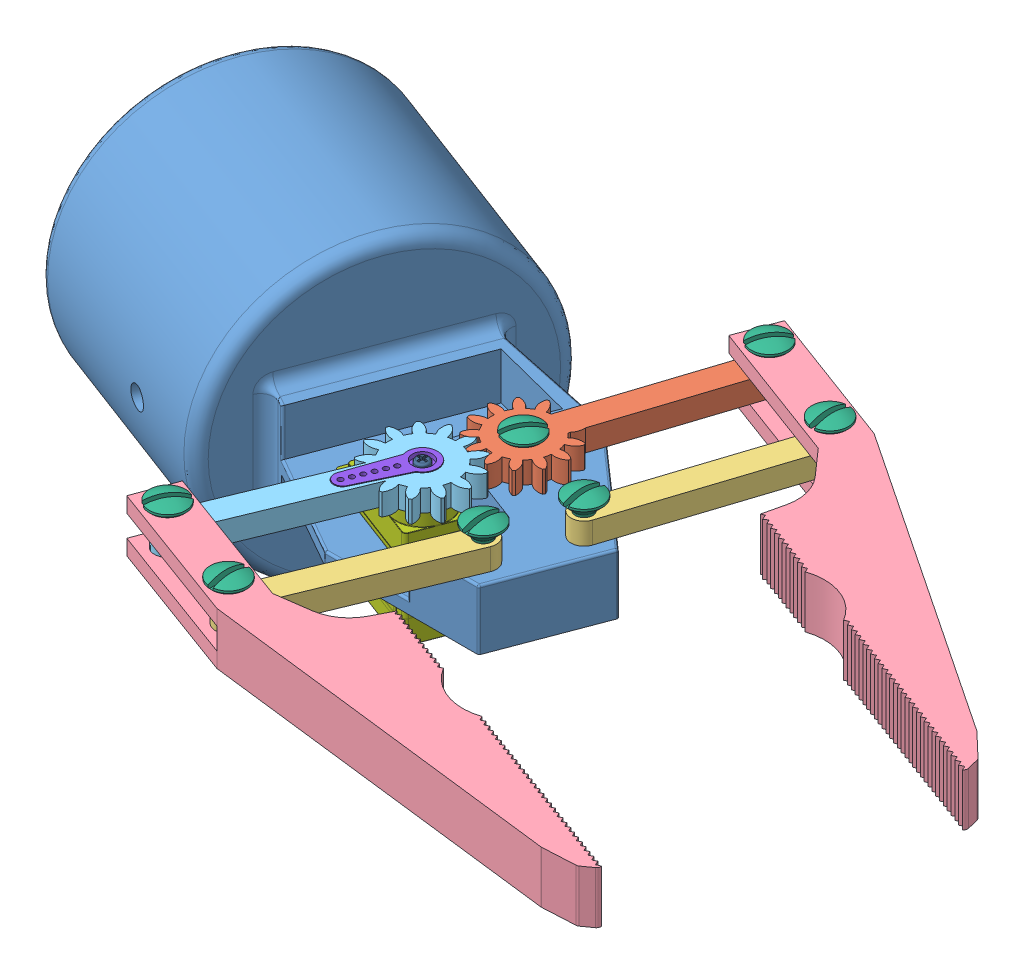
SolidWorks assembly ClawMK2, configuration Default. Lengths in mm.
Overall size (235.04 69 163.29).
19 component instances, 10 part files, 45 mates.
Components (placement in the parent):
- Base-1: Base [Default] at (-1.2919 74.4344 -5.5304) x (-0.353674 0 0.935369) z (-0.935369 0 -0.353674) size (69 69 125)
- Gear2_nocutout-1: Gear2_nocutout [Default] at (67.5688 95.9472 -64.8108) x (0 1 0) z (-0.438891 0 0.89854) size (5 20.52 57.89)
- Connector-1: Connector [Default] at (33.7567 88.2344 -25.927) x (0.308447 0 -0.951241) z (0.951241 0 0.308447) size (51 5 6)
- Claw-3: Claw [Default] at (30.1882 84.7344 -51.2331) x (0.937424 0 0.348189) z (-0.348189 0 0.937424) size (127.47 12 26.59)
- Gear1-2: Gear1 [Default] at (-16.659 95.9472 84.4421) x (0 1 0) z (-0.240649 0 -0.970612) size (5 40.44 50.3)
- Claw-4: Claw [Default] at (-7.186 96.7344 50.0535) x (0.938321 0 0.345766) z (0.345766 0 -0.938321) size (127.47 12 26.59)
- Connector-3: Connector [Default] at (11.8915 88.2344 33.1211) x (-0.3804 0 0.924822) z (-0.924822 0 -0.3804) size (51 5 6)
- countersunk slotted raised head screw_iso-1: countersunk slotted raised head screw_iso [ISO 2010 - M4 x 12 - 12N] at (18.4704 98.6344 -55.5855) x (0 -1 0) z (-0.546944 0 0.837169) size (12.98 8.4 8.31)
- countersunk slotted raised head screw_iso-3: countersunk slotted raised head screw_iso [ISO 2010 - M4 x 12 - 12N] at (40.6968 98.6344 -47.33) x (0 -1 0) z (0 0 1) size (12.98 8.4 8.31)
- countersunk slotted raised head screw_iso-4: countersunk slotted raised head screw_iso [ISO 2010 - M4 x 12 - 12N] at (26.8166 97.4344 -4.5241) x (0 -1 0) z (0 0 1) size (12.98 8.4 8.31)
- countersunk slotted raised head screw_iso-5: countersunk slotted raised head screw_iso [ISO 2010 - M4 x 12 - 12N] at (20.4505 97.4344 12.3126) x (0 -1 0) z (0 0 1) size (12.98 8.4 8.31)
- countersunk slotted raised head screw_iso-6: countersunk slotted raised head screw_iso [ISO 2010 - M4 x 12 - 12N] at (-18.9151 98.6344 45.7314) x (0 -1 0) z (-0.546944 0 0.837169) size (12.98 8.4 8.31)
- countersunk slotted raised head screw_iso-7: countersunk slotted raised head screw_iso [ISO 2010 - M4 x 12 - 12N] at (3.3325 98.6344 53.9296) x (0 -1 0) z (0 0 1) size (12.98 8.4 8.31)
- countersunk slotted raised head screw_iso-8: countersunk slotted raised head screw_iso [ISO 2010 - M4 x 12 - 12N] at (4.5903 95.1344 -12.7796) x (0 -1 0) z (-0.546944 0 0.837169) size (12.98 8.4 8.31)
- SG90 - Micro Servo 9g - Tower Pro.1-1: SG90 - Micro Servo 9g - Tower Pro.1 [Peça] at (-6.618 72.2844 2.2915) x (-0.935369 0 -0.353674) z (0.353674 0 -0.935369) size (32.1 29.95 12.4)
- SG90 - Micro Servo 9g - Tower Pro.2-3: SG90 - Micro Servo 9g - Tower Pro.2 [Peça] at (-1.8008 93.3844 4.1129) x (0.379469 0 -0.925204) z (0.925204 0 0.379469) size (19.5 3.8 6.9)
- SG90 - Micro Servo 9g - Tower Pro.5-1: SG90 - Micro Servo 9g - Tower Pro.5 [BS EN ISO 7045 - M2 x 8 - Z - 8S] at (-19.6196 81.5344 -2.6246) x (0 -1 0) z (0 0 1) size (9.57 4.8 4.8)
- SG90 - Micro Servo 9g - Tower Pro.5-2: SG90 - Micro Servo 9g - Tower Pro.5 [BS EN ISO 7045 - M2 x 8 - Z - 8S] at (6.3836 81.5344 7.2075) x (0 -1 0) z (0 0 1) size (9.57 4.8 4.8)
- SG90 - Micro Servo 9g - Tower Pro.6-5: SG90 - Micro Servo 9g - Tower Pro.6 [BS EN ISO 7045 - M2 x 4 - Z - 4S] at (-1.8008 93.6844 4.1129) x (0 -1 0) z (0 0 1) size (5.28 3.1 3.1)
Mates (geometry in assembly coordinates):
- Coincident3: coincident anti-aligned: plane of Base-1 through (-1.2919 88.2344 -5.5304) normal (0 1 0); plane of Gear2_nocutout-1 through (0.3646 88.2344 -12.9042) normal (0 -1 0)
- Concentric2: concentric anti-aligned: cylinder of Base-1 through (26.8166 84.4344 -4.5241) axis (0 1 0) radius 1.85; cylinder of Connector-1 through (26.8166 93.2344 -4.5241) axis (0 -1 0) radius 2
- Coincident8: coincident anti-aligned: plane of Base-1 through (-1.2919 88.2344 -5.5304) normal (0 1 0); plane of Connector-1 through (26.8166 88.2344 -4.5241) normal (0 -1 0)
- Concentric5: concentric aligned: cylinder of Connector-1 through (40.6968 93.2344 -47.33) axis (0 -1 0) radius 2; cylinder of Claw-3 through (40.6968 96.7344 -47.33) axis (0 -1 0) radius 2
- Coincident11: coincident anti-aligned: plane of Connector-1 through (26.8166 93.2344 -4.5241) normal (0 1 0); plane of Claw-3 through (15.5242 93.2344 -62.0136) normal (0 -1 0)
- Concentric11: concentric aligned: cylinder of Base-1 through (4.5903 84.4344 -12.7796) axis (0 1 0) radius 1.85; cylinder of Gear2_nocutout-1 through (4.5903 88.2344 -12.7796) axis (0 1 0) radius 2
- Coincident17: coincident anti-aligned: plane of Base-1 through (-1.2919 88.2344 -5.5304) normal (0 1 0); plane of Gear2_nocutout-1 through (0.3646 88.2344 -12.9042) normal (0 -1 0)
- Concentric12: concentric anti-aligned: cylinder of Gear2_nocutout-1 through (18.4704 88.2344 -55.5855) axis (0 1 0) radius 2; cylinder of Claw-3 through (18.4704 96.7344 -55.5855) axis (0 -1 0) radius 2
- Coincident18: coincident anti-aligned: plane of Gear2_nocutout-1 through (0.3646 93.2344 -12.9042) normal (0 1 0); plane of Claw-3 through (15.5242 93.2344 -62.0136) normal (0 -1 0)
- Coincident19: coincident anti-aligned: plane of Base-1 through (-1.2919 88.2344 -5.5304) normal (0 1 0); plane of Gear1-2 through (1.7395 88.2344 1.3199) normal (0 -1 0)
- Concentric14: concentric aligned: cylinder of Gear1-2 through (-18.9151 88.2344 45.7314) axis (0 1 0) radius 2; cylinder of Claw-4 through (-18.9151 84.7344 45.7314) axis (0 1 0) radius 2
- Coincident20: coincident anti-aligned: plane of Gear1-2 through (1.7395 93.2344 1.3199) normal (0 1 0); plane of Claw-4 through (-25.3355 93.2344 48.6942) normal (0 -1 0)
- Concentric16: concentric anti-aligned: cylinder of Base-1 through (20.4505 84.4344 12.3126) axis (0 1 0) radius 1.85; cylinder of Connector-3 through (20.4505 93.2344 12.3126) axis (0 -1 0) radius 2
- Coincident21: coincident anti-aligned: plane of Base-1 through (-1.2919 88.2344 -5.5304) normal (0 1 0); plane of Connector-3 through (20.4505 88.2344 12.3126) normal (0 -1 0)
- Concentric17: concentric anti-aligned: cylinder of Claw-4 through (3.3325 84.7344 53.9296) axis (0 1 0) radius 2; cylinder of Connector-3 through (3.3325 93.2344 53.9296) axis (0 -1 0) radius 2
- Coincident22: coincident anti-aligned: plane of Claw-4 through (-25.3355 93.2344 48.6942) normal (0 -1 0); plane of Connector-3 through (20.4505 93.2344 12.3126) normal (0 1 0)
- GearMate1: gear = 1 : 1 mm: cylinder of Gear2_nocutout-1 through (4.5903 88.2344 -12.7796) axis (0 1 0) radius 10.3821; cylinder of Gear1-2 through (-1.8008 88.2344 4.1129) axis (0 1 0) radius 7.7506
- Coincident23: coincident anti-aligned: plane of Claw-4 through (-25.3355 93.2344 48.6942) normal (0 -1 0); plane of Connector-3 through (20.4505 93.2344 12.3126) normal (0 1 0)
- Concentric19: concentric anti-aligned: cylinder of Connector-3 through (20.4505 93.2344 12.3126) axis (0 -1 0) radius 2; cylinder of countersunk slotted raised head screw_iso-5 through (20.4505 113.3094 12.3126) axis (0 1 0) radius 2
- Coincident25: coincident anti-aligned: plane of Base-1 through (20.4505 84.4344 12.3126) normal (0 1 0); plane of countersunk slotted raised head screw_iso-5 through (20.4505 84.4344 12.3126) normal (0 -1 0)
- Coincident26: coincident anti-aligned: plane of Base-1 through (26.8166 84.4344 -4.5241) normal (0 1 0); plane of countersunk slotted raised head screw_iso-4 through (26.8166 84.4344 -4.5241) normal (0 -1 0)
- Concentric20: concentric anti-aligned: cylinder of Connector-1 through (26.8166 93.2344 -4.5241) axis (0 -1 0) radius 2; cylinder of countersunk slotted raised head screw_iso-4 through (26.8166 113.3094 -4.5241) axis (0 1 0) radius 2
- Concentric23: concentric anti-aligned: cylinder of Connector-1 through (40.6968 93.2344 -47.33) axis (0 -1 0) radius 2; cylinder of countersunk slotted raised head screw_iso-3 through (40.6968 114.5094 -47.33) axis (0 1 0) radius 2
- Coincident27: coincident aligned: plane of Claw-3 through (30.1882 96.7344 -51.2331) normal (0 1 0); plane of countersunk slotted raised head screw_iso-3 through (41.2968 96.7344 -51.53) normal (0 1 0)
- Concentric25: concentric aligned: cylinder of Gear2_nocutout-1 through (18.4704 88.2344 -55.5855) axis (0 1 0) radius 2; cylinder of countersunk slotted raised head screw_iso-1 through (18.4704 114.5094 -55.5855) axis (0 1 0) radius 2
- Coincident30: coincident aligned: plane of Claw-3 through (30.1882 96.7344 -51.2331) normal (0 1 0); plane of countersunk slotted raised head screw_iso-1 through (21.2699 96.7344 -58.7735) normal (0 1 0)
- Concentric27: concentric aligned: cylinder of Claw-4 through (-18.9151 84.7344 45.7314) axis (0 1 0) radius 2; cylinder of countersunk slotted raised head screw_iso-6 through (-18.9151 114.5094 45.7314) axis (0 1 0) radius 2
- Coincident31: coincident aligned: plane of Claw-4 through (-7.186 96.7344 50.0535) normal (0 1 0); plane of countersunk slotted raised head screw_iso-6 through (-16.1156 96.7344 42.5435) normal (0 1 0)
- Concentric28: concentric anti-aligned: cylinder of Connector-3 through (3.3325 93.2344 53.9296) axis (0 -1 0) radius 2; cylinder of countersunk slotted raised head screw_iso-7 through (3.3325 114.5094 53.9296) axis (0 1 0) radius 2
- Coincident32: coincident aligned: plane of Claw-4 through (-7.186 96.7344 50.0535) normal (0 1 0); plane of countersunk slotted raised head screw_iso-7 through (3.9325 96.7344 49.7296) normal (0 1 0)
- Concentric29: concentric aligned: cylinder of Gear2_nocutout-1 through (4.5903 88.2344 -12.7796) axis (0 1 0) radius 2; cylinder of countersunk slotted raised head screw_iso-8 through (4.5903 111.0094 -12.7796) axis (0 1 0) radius 2
- Coincident33: coincident aligned: plane of Gear2_nocutout-1 through (0.3646 93.2344 -12.9042) normal (0 1 0); plane of countersunk slotted raised head screw_iso-8 through (7.3898 93.2344 -15.9676) normal (0 1 0)
- Coincident34: coincident anti-aligned: plane of Base-1 through (6.0623 67.4344 0.5645) normal (-0.935369 0 -0.353674); plane of SG90 - Micro Servo 9g - Tower Pro.1-1 through (5.7617 77.4344 1.3596) normal (0.935369 0 0.353674)
- Coincident35: coincident anti-aligned: plane of Base-1 through (-1.2919 77.4344 -5.5304) normal (0 1 0); plane of SG90 - Micro Servo 9g - Tower Pro.1-1 through (9.4564 77.4344 2.7566) normal (0 -1 0)
- Coincident36: coincident anti-aligned: plane of Base-1 through (6.0623 67.4344 0.5645) normal (-0.353674 0 0.935369); plane of SG90 - Micro Servo 9g - Tower Pro.1-1 through (5.2673 77.4344 0.2639) normal (0.353674 0 -0.935369)
- Concentric33: concentric aligned: cylinder of SG90 - Micro Servo 9g - Tower Pro.1-1 through (-1.8008 91.5844 4.1129) axis (0 1 0) radius 0.8; cylinder of SG90 - Micro Servo 9g - Tower Pro.2-3 through (-1.8008 93.3844 4.1129) axis (0 1 0) radius 1.05
- Concentric34: concentric aligned: cylinder of Gear1-2 through (-1.8008 88.2344 4.1129) axis (0 1 0) radius 3.5; cylinder of SG90 - Micro Servo 9g - Tower Pro.2-3 through (-1.8008 91.9844 4.1129) axis (0 1 0) radius 3.45
- Concentric351: concentric anti-aligned: cylinder of SG90 - Micro Servo 9g - Tower Pro.1-1 through (-19.6196 61.7344 -2.6246) axis (0 1 0) radius 1.1; cylinder of SG90 - Micro Servo 9g - Tower Pro.5-1 through (-19.6196 80.4344 -2.6246) axis (0 -1 0) radius 2.4
- Coincident421: coincident anti-aligned: plane of SG90 - Micro Servo 9g - Tower Pro.1-1 through (9.4564 79.9344 2.7566) normal (0 1 0); plane of SG90 - Micro Servo 9g - Tower Pro.5-1 through (-18.6196 79.9344 -2.6246) normal (0 -1 0)
- Concentric361: concentric anti-aligned: cylinder of SG90 - Micro Servo 9g - Tower Pro.1-1 through (6.3836 61.7344 7.2075) axis (0 1 0) radius 1.1; cylinder of SG90 - Micro Servo 9g - Tower Pro.5-2 through (6.3836 80.4344 7.2075) axis (0 -1 0) radius 2.4
- Coincident431: coincident anti-aligned: plane of SG90 - Micro Servo 9g - Tower Pro.1-1 through (9.4564 79.9344 2.7566) normal (0 1 0); plane of SG90 - Micro Servo 9g - Tower Pro.5-2 through (7.3836 79.9344 7.2075) normal (0 -1 0)
- Coincident48: coincident anti-aligned: plane of SG90 - Micro Servo 9g - Tower Pro.2-3 through (-1.8008 92.3844 4.1129) normal (0 1 0); plane of SG90 - Micro Servo 9g - Tower Pro.6-5 through (-0.8008 92.3844 4.1129) normal (0 -1 0)
- Concentric38: concentric aligned: cylinder of SG90 - Micro Servo 9g - Tower Pro.2-3 through (-1.8008 93.3844 4.1129) axis (0 1 0) radius 1.05; cylinder of SG90 - Micro Servo 9g - Tower Pro.6-5 through (-1.8008 119.0844 4.1129) axis (0 1 0) radius 1
- Coincident49: coincident anti-aligned: plane of Gear1-2 through (-16.659 91.9844 84.4421) normal (0 1 0); plane of SG90 - Micro Servo 9g - Tower Pro.2-3 through (-1.8008 91.9844 4.1129) normal (0 -1 0)
- Parallel4: parallel anti-aligned: plane of Gear1-2 through (-33.1993 91.9844 76.5781) normal (-0.903122 0 -0.429384); plane of SG90 - Micro Servo 9g - Tower Pro.2-3 through (-0.1873 91.9844 7.1623) normal (0.903122 0 0.429384)
